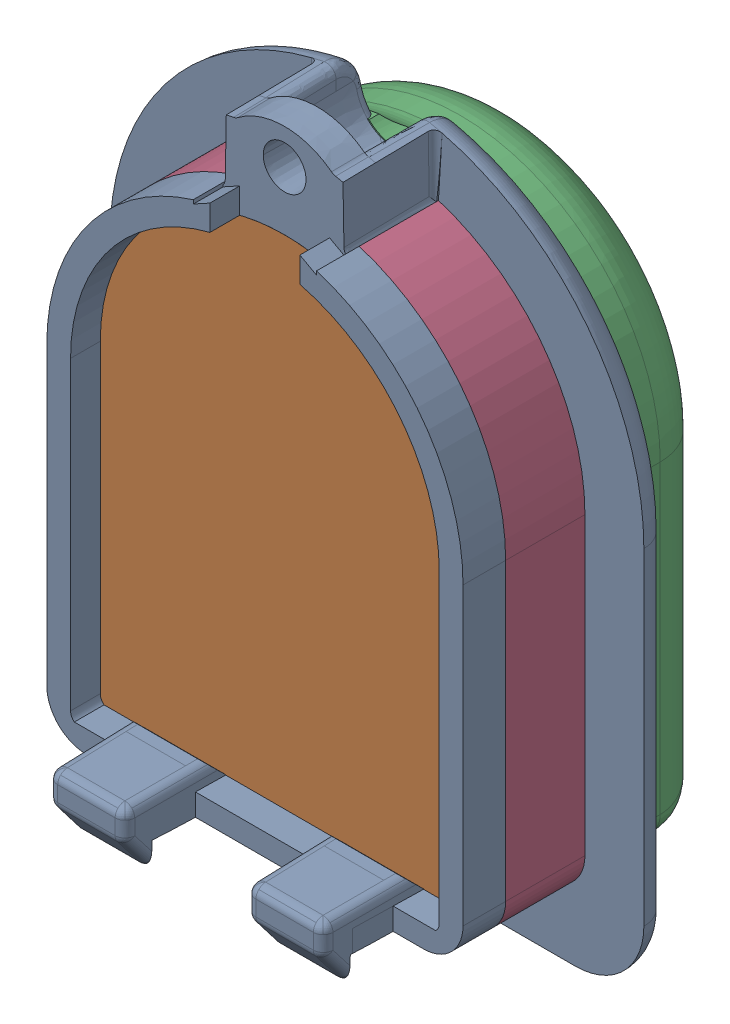
SolidWorks assembly Board, configuration 默认. Lengths in mm.
Overall size (26.95 34.26 16.66).
6 component instances, 6 part files, 9 mates.
Components (placement in the parent):
- BoardOriginBody-1: BoardOriginBody [默认] at origin size (26.95 34.26 11.2)
- BoardLens-1: BoardLens [默认] at (0 0 0.5) size (18.6 25.2 5.65)
- BoardoutSkin-1: BoardoutSkin [默认] at (0 -3.3 0.5) x (-1 0 0) z (0 0 -1) size (21.8 28.5 6)
- BoardTransBody-1: BoardTransBody [默认] at origin size (21 26.93 4)
- BoardInsideSKin-3: BoardInsideSKin [默认] at (0 -3.3 0.5) x (-1 0 0) z (0 0 -1) size (18.6 25.2 5.2)
- BoardMarker-1: BoardMarker [默认] at (-13.2658 -7.1947 -4.3) x (0 1 0) z (0 0 -1) size (20.45 14.3 0.4)
Mates (geometry in assembly coordinates):
- 重合1: coordinate: point of OriginBody-1
- 重合2: coincident anti-aligned: plane of OriginBody-1 through (0 0 1.5) normal (0 0 1); plane of TransBody-1 through (9.35 -17.0923 1.5) normal (0 0 -1)
- 同心1: concentric aligned: cylinder of OriginBody-1 through (0 0 7.65) axis (0 0 -1) radius 10.5; cylinder of TransBody-1 through (0 0 7.65) axis (0 0 -1) radius 10.5
- 重合3: coincident anti-aligned: plane of OriginBody-1 through (-2.4881 -0.1521 7.65) normal (-0.998137 -0.061005 0); plane of TransBody-1 through (-2.4881 -0.1521 7.65) normal (0.998137 0.061005 0)
- 宽度1: width anti-aligned: plane of TransBody-1 through (10.5 0 7.65) normal (1 0 0); plane of TransBody-1 through (-10.5 0 7.65) normal (-1 0 0); plane of BoardLens-1 through (-9.3 0 6.15) normal (-1 0 0); plane of BoardLens-1 through (9.3 0 6.15) normal (1 0 0)
- 重合4: coincident anti-aligned: plane of BoardLens-1 through (-9.3 -15.9 6.15) normal (0 -1 0); plane of TransBody-1 through (0 -15.9 56.847) normal (0 1 0)
- 重合5: coincident aligned: plane of OriginBody-1 through (-8.8 -15.4 0.5) normal (0 0 -1); plane of BoardLens-1 through (0 0 0.5) normal (0 0 -1)
- 同心3: concentric aligned: cone of OriginBody-1 through (0 12.25 4.5) axis (0 0 1); cylinder of outSkin-1 through (0 12.25 -9.5) axis (0 0 1) radius 2.0018
- 重合7: coincident anti-aligned: plane of OriginBody-1 through (-8.8 -15.4 0.5) normal (0 0 -1); plane of outSkin-1 through (-8.8 -15.4 0.5) normal (0 0 1)
